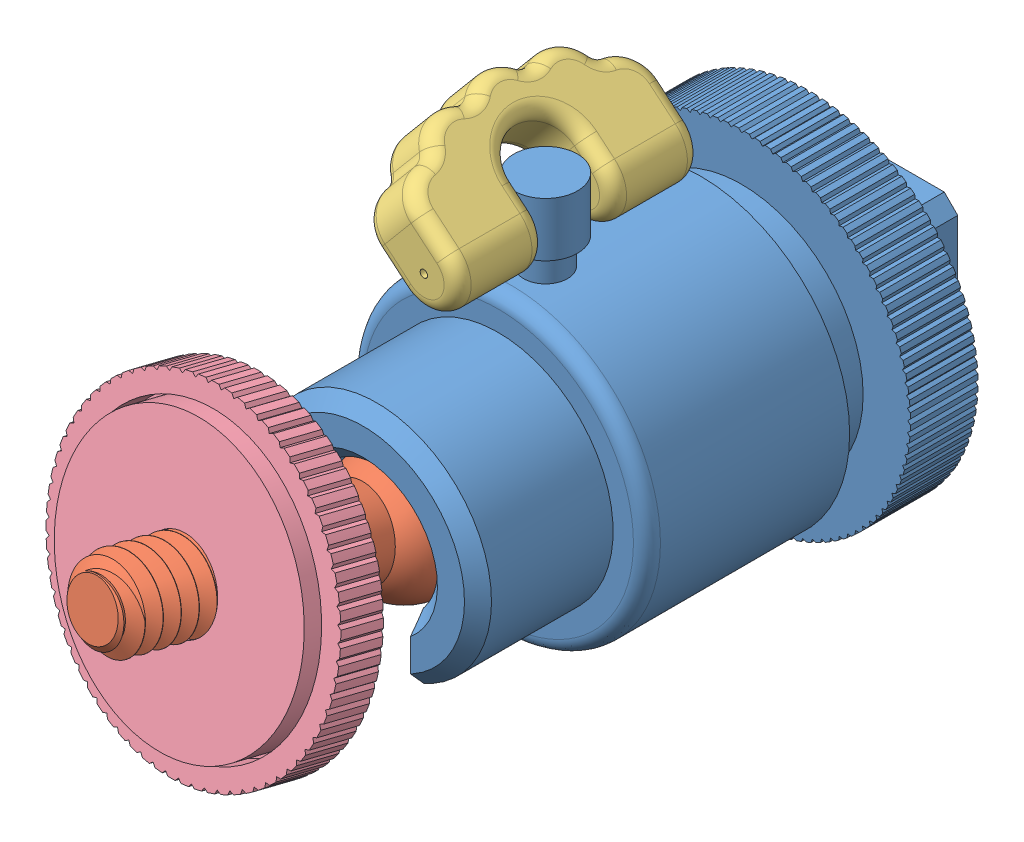
SolidWorks assembly arm_assembly, configuration По умолчанию. Lengths in mm.
Overall size (29.47 34.25 55.18).
4 component instances, 4 part files, 4 mates.
Components (placement in the parent):
- base-1: base [По умолчанию] at (-78.812 29.2185 42.0982) size (25 29.5 35)
- 1.4-1: 1.4 [По умолчанию] at (-78.812 29.2185 64.0452) x (0.997287 0.036081 0.064159) z (0.023037 -0.980828 0.193509) size (9 27.05 9)
- thumb_screw-1: thumb_screw [По умолчанию] at (-78.812 44.2306 44.6037) x (0.643117 0.765768 0) z (0 0 1) size (5 10 18)
- bulb_screw-1: bulb_screw [По умолчанию] at (-79.8524 32.0686 78.615) x (-0.317759 0.926003 -0.203831) z (0.069911 -0.191506 -0.978998) size (23 23 6)
Mates (geometry in assembly coordinates):
- Концентричный1: concentric: sphere of base-1; sphere of 1.4-1
- Концентричный2: concentric anti-aligned: cylinder of base-1 through (-78.812 44.2306 32.0982) axis (0 0 1) radius 0.5536; cylinder of thumb_screw-1 through (-78.812 44.2306 62.6037) axis (0 0 -1) radius 0.2744
- Расстояние1: distance = 0.15 mm anti-aligned: plane of thumb_screw-1 through (-81.745 43.4291 56.1037) normal (0 0 -1); cylinder of base-1 through (-78.812 46.2185 53.594) axis (0 -1 0) radius 2.3597
- Концентричный3: concentric anti-aligned: cylinder of 1.4-1 through (-78.4973 28.3565 59.6387) axis (-0.069911 0.191506 0.978998) radius 3; cylinder of bulb_screw-1 through (-79.9224 32.2601 79.594) axis (0.069911 -0.191506 -0.978998) radius 3
